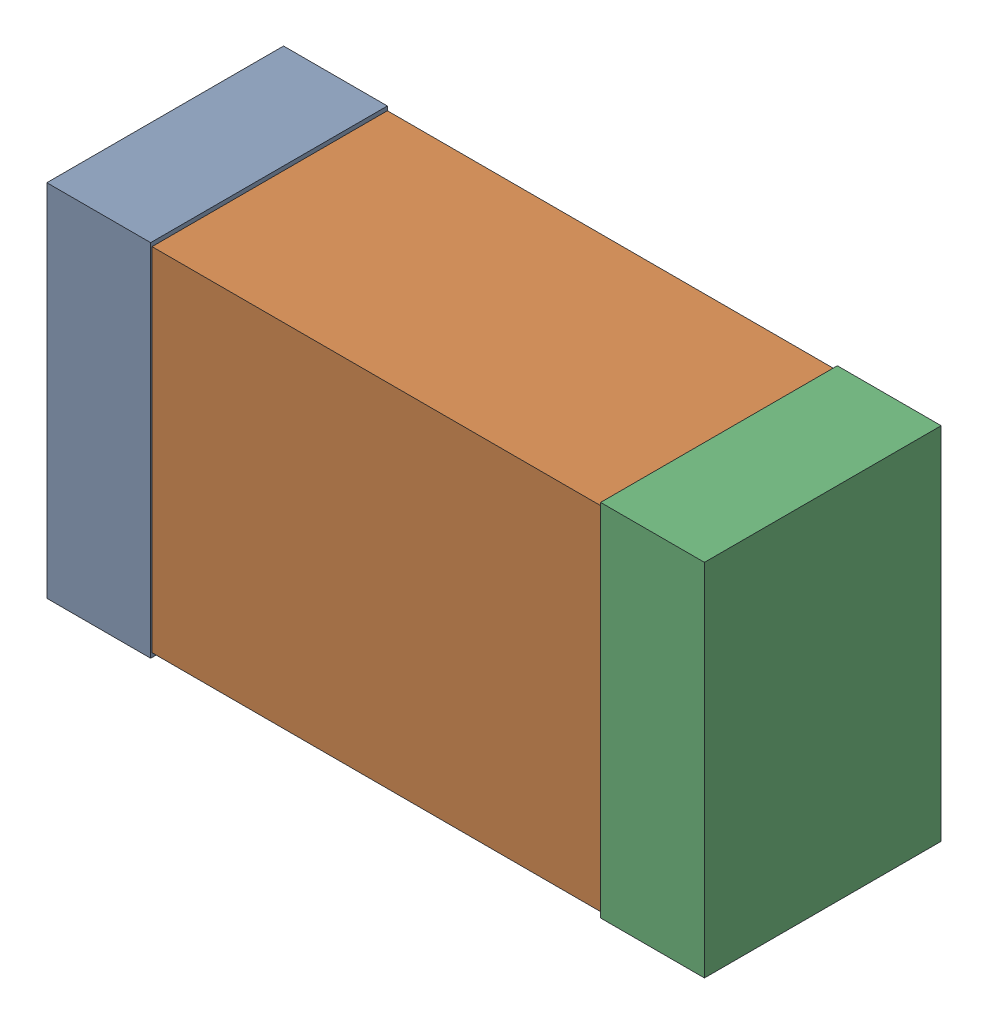
SolidWorks assembly R3_Motor_2Kanaloa_v2.0.0_Motor, configuration Default. Lengths in mm.
Overall size (2.38 1.3 0.85).
6 component instances, 2 part files, 0 mates.
Components (placement in the parent):
- 352877648-1: 352877648 [Default] at (126.821 65.786 0) size (0.38 1.3 0.85)
  - Extruded_14-1: Extruded_14 [Default] at origin size (0.38 1.3 0.85)
- 352877392-1: 352877392 [Default] at (127.821 65.786 0) size (2.2 1.27 0.85)
  - Extruded_15-1: Extruded_15 [Default] at origin size (2.2 1.27 0.85)
- 352877648-2: 352877648 [Default] at (128.821 65.786 0) size (0.38 1.3 0.85)
  - Extruded_14-1: Extruded_14 [Default] at origin size (0.38 1.3 0.85)
